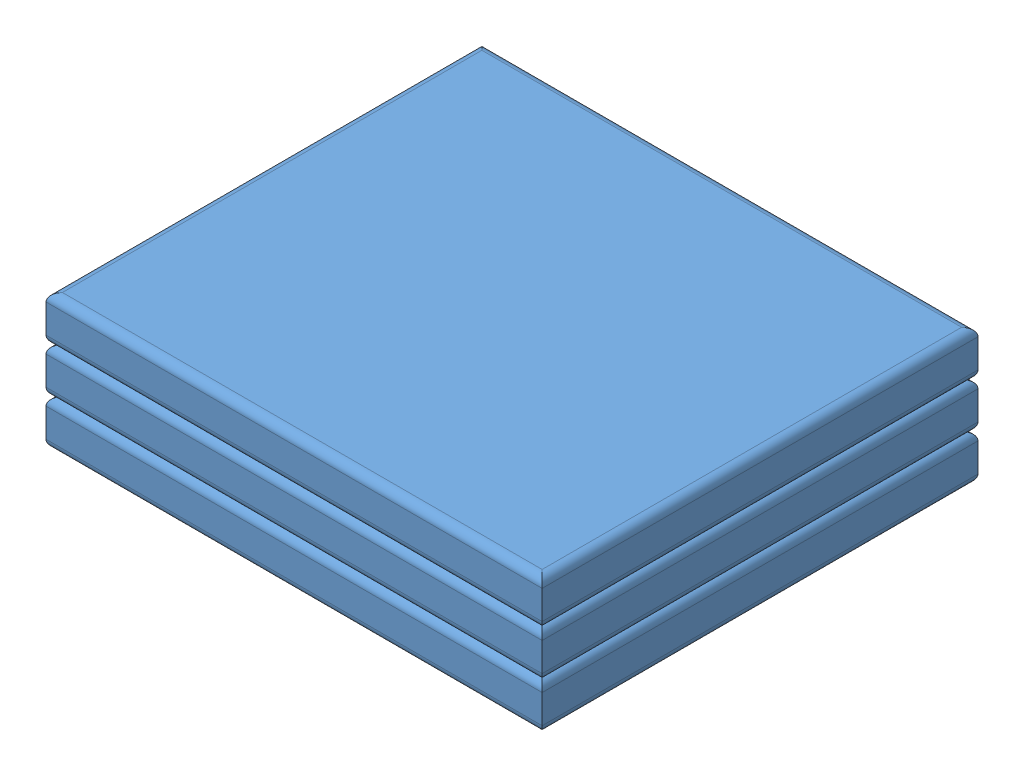
SolidWorks assembly LiPo 1-Cell 6Ah, configuration Default. Lengths in mm.
Overall size (60.5 16.5 53.15).
3 component instances, 1 part files, 0 mates.
Components (placement in the parent):
- LiPo Cell-1: LiPo Cell [Default] at (-54.3114 2.869 35.4544) size (60.5 5.5 53.15)
- LiPo Cell-2: LiPo Cell [Default] at (-54.3114 8.369 35.4544) size (60.5 5.5 53.15)
- LiPo Cell-3: LiPo Cell [Default] at (-54.3114 13.869 35.4544) size (60.5 5.5 53.15)
